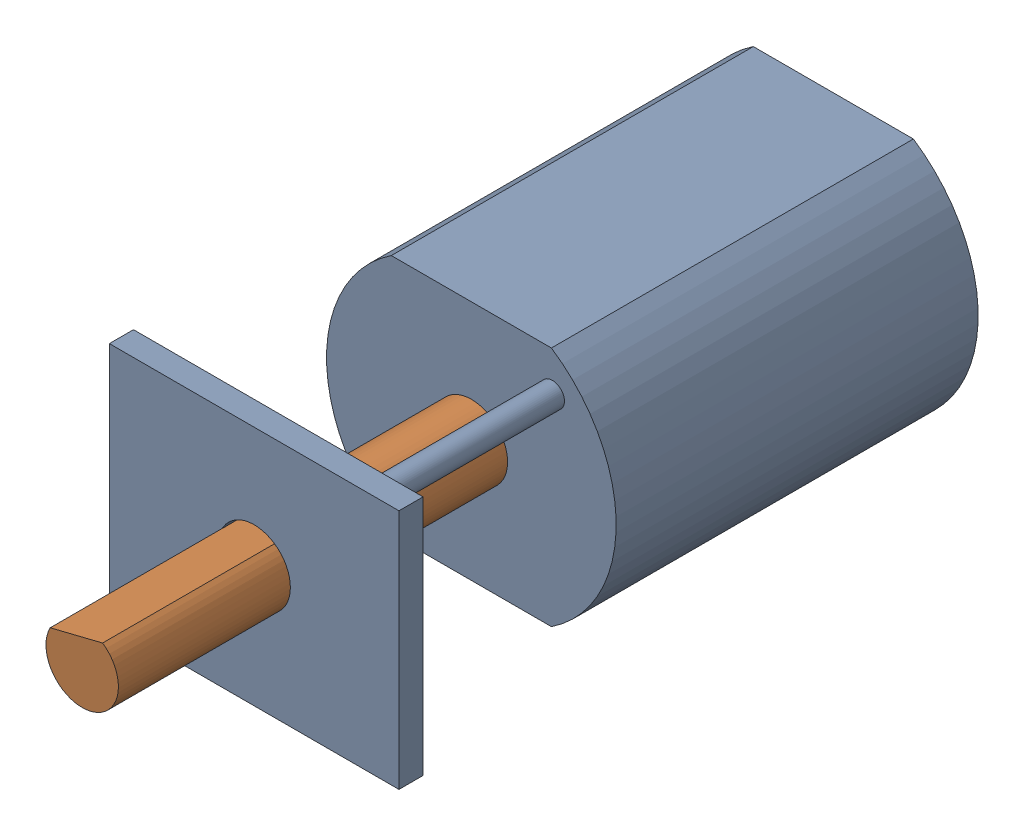
SolidWorks assembly N20 motor, configuration Default. Lengths in mm.
Overall size (12 10 32.12).
2 component instances, 2 part files, 2 mates.
Components (placement in the parent):
- N20 body-1: N20 body [Default] at (1.242 1.0566 -1.3732) size (12 10 25)
- N20 shaft-1: N20 shaft [Default] at (1.242 1.0566 6.1893) x (0.970619 0.240621 0) z (0 0 1) size (3 3 32.12)
Mates (geometry in assembly coordinates):
- Coincident4: coincident aligned: plane of N20 body-1 through (1.242 1.0566 -9.8732) normal (0 0 -1); plane of N20 shaft-1 through (1.242 1.0566 -9.8732) normal (0 0 -1)
- Concentric1: concentric aligned: circle of N20 body-1; circle of N20 shaft-1
